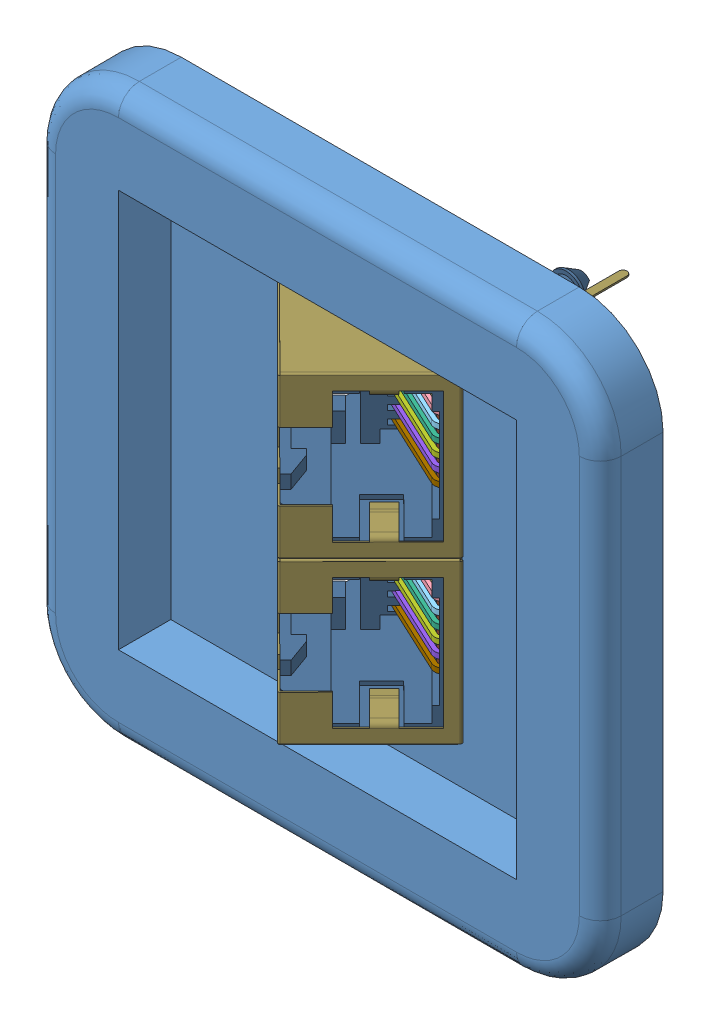
SolidWorks assembly Steckdose-RJ45, configuration Standard. Lengths in mm.
Overall size (54 54 25.23).
25 component instances, 12 part files, 6 mates.
Components (placement in the parent):
- Buchse-RJ45-1: Buchse-RJ45 [Standard] at (-88.9836 -48.9043 64.0274) size (54 54 6)
- 65864-1: 65864 [Default] at (-11.8405 9.7148 53.1274) size (17.49 15.42 25.23)
  - 65864_01-1: 65864_01 [Default] at origin size (9.69 0.75 13.83)
  - 65864_02-1: 65864_02 [Default] at origin size (9.44 0.68 13.83)
  - 65864_03-1: 65864_03 [Default] at origin size (9.69 0.61 13.84)
  - 65864_04-1: 65864_04 [Default] at origin size (9.44 0.54 13.83)
  - 65864_05-1: 65864_05 [Default] at origin size (9.69 0.54 13.82)
  - 65864_06-1: 65864_06 [Default] at origin size (9.44 0.6 13.83)
  - 65864_07-1: 65864_07 [Default] at origin size (9.69 0.68 13.83)
  - 65864_08-1: 65864_08 [Default] at origin size (9.44 0.75 13.83)
  - 65864_09-1: 65864_09 [Default] at origin size (17.11 15.1 23.65)
  - 65864_10-1: 65864_10 [Default] at origin size (6.36 10.31 6.36)
  - 65864_11-1: 65864_11 [Default] at origin size (17.49 15.42 25.23)
- 65864-2: 65864 [Default] at (-11.8405 -5.6852 53.1274) size (17.49 15.42 25.23)
  - 65864_01-1: 65864_01 [Default] at origin size (9.69 0.75 13.83)
  - 65864_02-1: 65864_02 [Default] at origin size (9.44 0.68 13.83)
  - 65864_03-1: 65864_03 [Default] at origin size (9.69 0.61 13.84)
  - 65864_04-1: 65864_04 [Default] at origin size (9.44 0.54 13.83)
  - 65864_05-1: 65864_05 [Default] at origin size (9.69 0.54 13.82)
  - 65864_06-1: 65864_06 [Default] at origin size (9.44 0.6 13.83)
  - 65864_07-1: 65864_07 [Default] at origin size (9.69 0.68 13.83)
  - 65864_08-1: 65864_08 [Default] at origin size (9.44 0.75 13.83)
  - 65864_09-1: 65864_09 [Default] at origin size (17.11 15.1 23.65)
  - 65864_10-1: 65864_10 [Default] at origin size (6.36 10.31 6.36)
  - 65864_11-1: 65864_11 [Default] at origin size (17.49 15.42 25.23)
Mates (geometry in assembly coordinates):
- Deckungsgleich1: coincident aligned: plane of 65864-2/65864_09-1 through (-20.3955 -13.2352 47.0274) normal (0 0 -1); plane of 65864-1/65864_09-1 through (-20.3955 2.1648 47.0274) normal (0 0 -1)
- Deckungsgleich2: coincident anti-aligned: plane of 65864-1/65864_11-1 through (-11.8432 2.0148 47.8874) normal (0 -1 0); plane of 65864-2/65864_11-1 through (-11.8432 2.0148 47.8874) normal (0 1 0)
- Abstand1: distance = 11 mm aligned: plane of 65864-2/65864_09-1 through (-20.3955 -13.2352 47.0274) normal (0 0 -1); plane of Buchse-RJ45-1 through (-30.9855 -16.9852 58.0274) normal (0 0 -1)
- Deckungsgleich4: coincident aligned: plane of 65864-1/65864_09-1 through (-20.3955 2.1648 59.2274) normal (-1 0 0); plane of 65864-2/65864_09-1 through (-20.3955 -13.2352 59.2274) normal (-1 0 0)
- Deckungsgleich6: coincident anti-aligned: plane of Buchse-RJ45-1 through (-3.2855 -13.3852 49.0274) normal (-1 0 0); plane of 65864-1/65864_09-1 through (-3.2855 2.1648 47.0274) normal (1 0 0)
- Deckungsgleich7: coincident anti-aligned: plane of Buchse-RJ45-1 through (-20.6855 -13.3852 49.0274) normal (0 1 0); plane of 65864-2/65864_11-1 through (-11.8432 -13.3852 47.8874) normal (0 -1 0)
